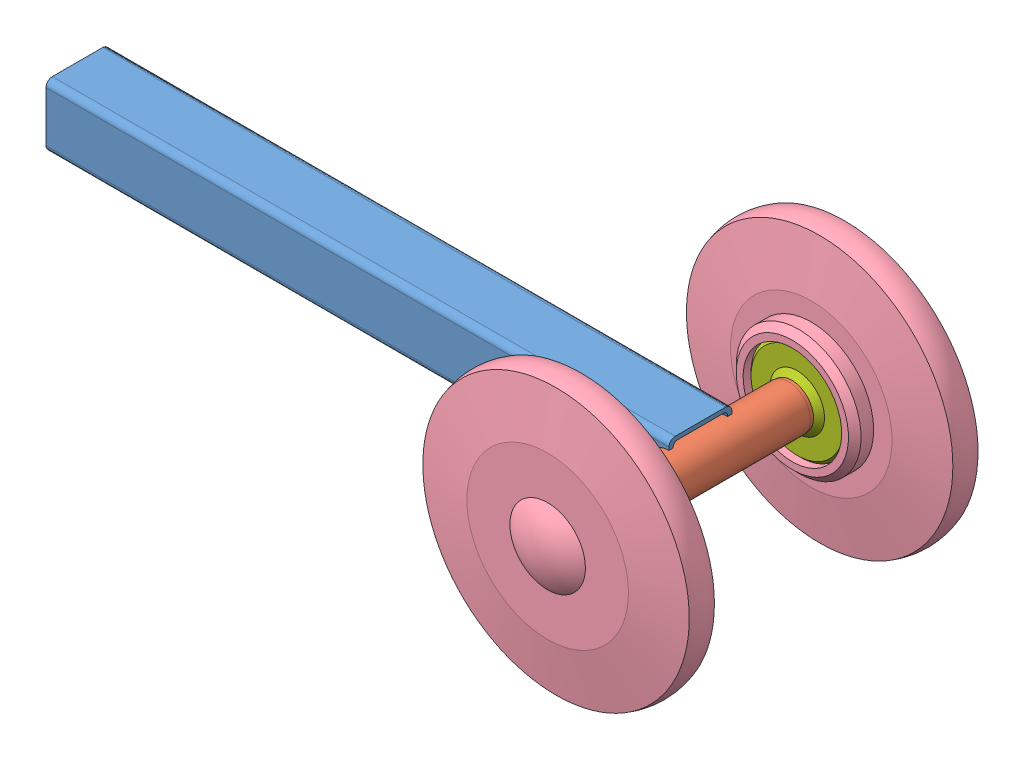
SolidWorks assembly ТП.016.02.02.00 - Натяжитель гусеницы, configuration 00. Lengths in mm.
Overall size (371.74 149.44 157.68).
18 component instances, 9 part files, 12 mates.
Components (placement in the parent):
- ТП.016.02.02.01.00 - Толкатель натяжки-1: ТП.016.02.02.01.00 - Толкатель натяжки [00] at origin size (311.12 30 133.68)
  - ТП.016.02.02.01.01 - Шток натяжного ролика (30х30)-1: ТП.016.02.02.01.01 - Шток натяжного ролика (30х30) [--] at origin size (297.02 30 30)
  - ТП.016.02.01.01.02(02) - Ось цельная 21_3мм-1: ТП.016.02.01.01.02(02) - Ось цельная 21_3мм [--] x (0 0 1) z (-0.910058 0.41448 0) size (133.68 21.3 21.3)
  - ТП.016.02.02.01.02 - Заглушка штока-1: ТП.016.02.02.01.02 - Заглушка штока [--] at (-297.0168 0 0) x (0 -1 0) z (1 0 0) size (26 26 20)
- Каток 129(47) в сборе-1: Каток 129(47) в сборе [00] at (0 0 62.8416) x (0 0 1) z (1 0 0) size (35.7 129 129)
  - Каток 129(47)-1: Каток 129(47) [--] at origin size (35 129 129)
  - Подшипник ГОСТ 8338-75 -1: Подшипник ГОСТ 8338-75  [Подшипник 204 ГОСТ 8338-75] at (-1 0 0) x (1 0 0) z (0 -0.327433 -0.944874) size (14 47 47)
  - Стопор внутренний до 165мм (ГОСТ 13943-86)-1: Стопор внутренний до 165мм (ГОСТ 13943-86) [Кольцо 47] at (-8 0 0) x (0 0.910839 0.412761) z (-1 0 0) size (49.5 51.2 1.7)
  - Сальник 47х20-1: Сальник 47х20 [--] at (-9.7 0 0) x (-1 0 0) z (0 0.937697 -0.347453) size (10 47 47)
- Каток 129(47) в сборе-2: Каток 129(47) в сборе [00] at (0 0 -62.8416) x (0 0 -1) z (-0.173648 0.984808 0) size (35.7 129 129)
  - Каток 129(47)-1: Каток 129(47) [--] at origin size (35 129 129)
  - Подшипник ГОСТ 8338-75 -1: Подшипник ГОСТ 8338-75  [Подшипник 204 ГОСТ 8338-75] at (-1 0 0) x (1 0 0) z (0 -0.327433 -0.944874) size (14 47 47)
  - Стопор внутренний до 165мм (ГОСТ 13943-86)-1: Стопор внутренний до 165мм (ГОСТ 13943-86) [Кольцо 47] at (-8 0 0) x (0 0.910839 0.412761) z (-1 0 0) size (49.5 51.2 1.7)
  - Сальник 47х20-1: Сальник 47х20 [--] at (-9.7 0 0) x (-1 0 0) z (0 0.937697 -0.347453) size (10 47 47)
- ТП.016.02.02.02 - Шайба оси-1: ТП.016.02.02.02 - Шайба оси [--] at (0 0 -66.3614) x (0 0 1) z (0.48394 0.875101 0) size (4 24 24)
- Болты с шестигранной головкой кт.В (ГОСТ 7798-70)-1: Болты с шестигранной головкой кт.В (ГОСТ 7798-70) [Болт М6-6gx14(S10) ГОСТ 7798-77] at (0 0 -69.3416) x (0 0 1) z (0.143998 -0.989578 0) size (18 10.9 10)
- ТП.016.02.02.02 - Шайба оси-2: ТП.016.02.02.02 - Шайба оси [--] at (0 0 66.3614) x (0 0 -1) z (0.777771 0.628548 0) size (4 24 24)
- Болты с шестигранной головкой кт.В (ГОСТ 7798-70)-2: Болты с шестигранной головкой кт.В (ГОСТ 7798-70) [Болт М6-6gx14(S10) ГОСТ 7798-77] at (0 0 69.3416) x (0 0 -1) z (-0.999549 -0.030028 0) size (18 10.9 10)
Mates (geometry in assembly coordinates):
- Концентричный1: concentric: cylinder of ТП.016.02.02.01.00 - Толкатель натяжки-1/ТП.016.02.01.01.02(02) - Ось цельная 21_3мм-1 through (0 0 66.8416) axis (0 0 1) radius 10; cylinder of Каток 129(47) в сборе-1/Подшипник ГОСТ 8338-75 -1 through (0 0 -938.1584) axis (0 0 -1) radius 10
- Расстояние1: distance = 2 mm: plane of Каток 129(47) в сборе-1/Подшипник ГОСТ 8338-75 -1 through (3.7655 10.8661 68.8416) normal (0 0 1); plane of ТП.016.02.02.01.00 - Толкатель натяжки-1/ТП.016.02.01.01.02(02) - Ось цельная 21_3мм-1 through (0 0 66.8416) normal (0 0 1)
- Концентричный2: concentric: cylinder of ТП.016.02.02.01.00 - Толкатель натяжки-1/ТП.016.02.01.01.02(02) - Ось цельная 21_3мм-1 through (0 0 -66.8416) axis (0 0 -1) radius 10; cylinder of Каток 129(47) в сборе-2/Подшипник ГОСТ 8338-75 -1 through (0 0 938.1584) axis (0 0 1) radius 10
- Расстояние2: distance = 2 mm: plane of Каток 129(47) в сборе-2/Подшипник ГОСТ 8338-75 -1 through (10.0471 5.5951 -68.8416) normal (0 0 -1); plane of ТП.016.02.02.01.00 - Толкатель натяжки-1/ТП.016.02.01.01.02(02) - Ось цельная 21_3мм-1 through (0 0 -66.8416) normal (0 0 -1)
- Совпадение1: coincident: plane of Каток 129(47) в сборе-2/Подшипник ГОСТ 8338-75 -1 through (10.0471 5.5951 -68.8416) normal (0 0 -1); plane of ТП.016.02.02.02 - Шайба оси-1 through (10.5012 -5.8073 -68.8416) normal (0 0 1)
- Концентричный3: concentric: cylinder of Каток 129(47) в сборе-2/Подшипник ГОСТ 8338-75 -1 through (0 0 938.1584) axis (0 0 1) radius 10; cylinder of ТП.016.02.02.02 - Шайба оси-1 through (0 0 -70.8416) axis (0 0 -1) radius 10
- Концентричный4: concentric: cylinder of ТП.016.02.02.02 - Шайба оси-1 through (0 0 -70.8416) axis (0 0 -1) radius 3.25; cylinder of Болты с шестигранной головкой кт.В (ГОСТ 7798-70)-1 through (0 0 -1069.3416) axis (0 0 -1) radius 3
- Совпадение2: coincident: plane of ТП.016.02.02.02 - Шайба оси-1 through (7.4384 -4.1135 -69.3416) normal (0 0 -1); plane of Болты с шестигранной головкой кт.В (ГОСТ 7798-70)-1 through (-5.3932 -0.7848 -69.3416) normal (0 0 1)
- Концентричный5: concentric: cylinder of ТП.016.02.02.02 - Шайба оси-2 through (0 0 70.8416) axis (0 0 1) radius 3.25; cylinder of Болты с шестигранной головкой кт.В (ГОСТ 7798-70)-2 through (0 0 1069.3416) axis (0 0 1) radius 3
- Совпадение3: coincident: plane of ТП.016.02.02.02 - Шайба оси-2 through (-5.3427 6.6111 69.3416) normal (0 0 1); plane of Болты с шестигранной головкой кт.В (ГОСТ 7798-70)-2 through (0.1637 -5.4475 69.3416) normal (0 0 -1)
- Совпадение4: coincident: plane of Каток 129(47) в сборе-1/Подшипник ГОСТ 8338-75 -1 through (3.7655 10.8661 68.8416) normal (0 0 1); plane of ТП.016.02.02.02 - Шайба оси-2 through (-7.5426 9.3333 68.8416) normal (0 0 -1)
- Концентричный6: concentric: cylinder of Каток 129(47) в сборе-1/Подшипник ГОСТ 8338-75 -1 through (0 0 -938.1584) axis (0 0 -1) radius 10; cylinder of ТП.016.02.02.02 - Шайба оси-2 through (0 0 70.8416) axis (0 0 1) radius 10
